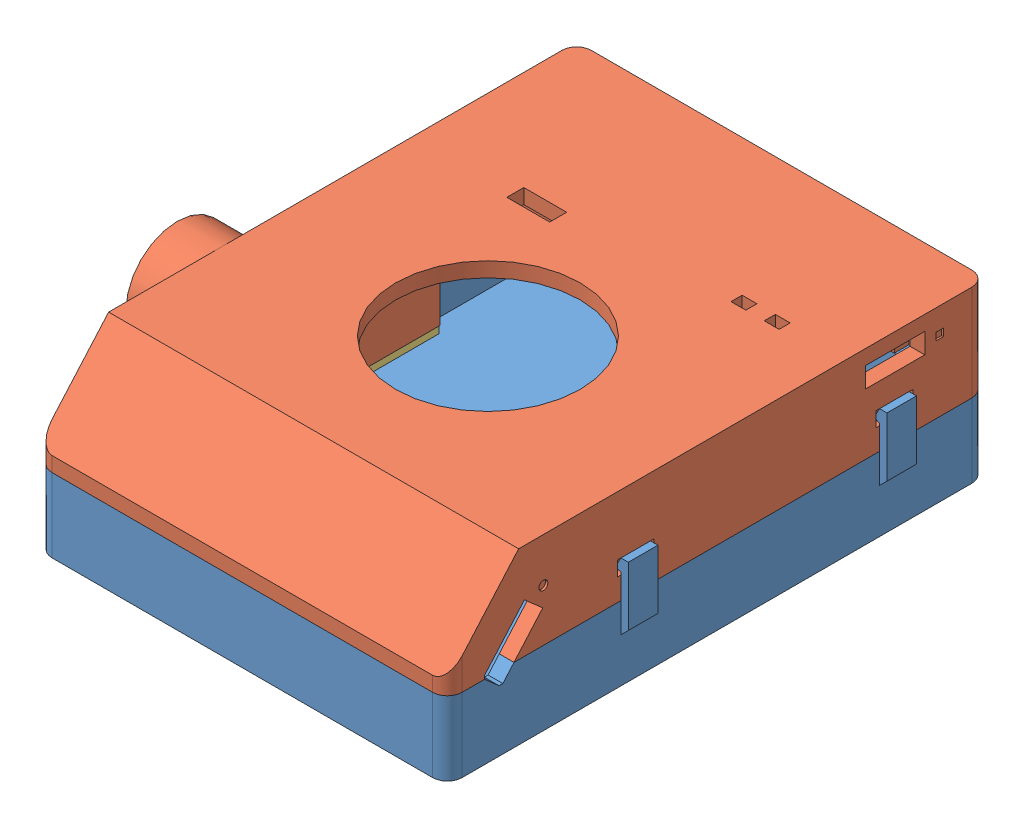
SolidWorks assembly Assem5, configuration Default. Lengths in mm.
Overall size (62.5 23 101.66).
4 component instances, 4 part files, 7 mates.
Components (placement in the parent):
- bottom shell 5-1: bottom shell 5 [Default] at (-8.039 40.5058 69.6202) size (57.5 15 73)
- top shell-1: top shell [Default] at (-8.039 63.5058 69.6202) x (1 0 0) z (0 0 -1) size (61.5 19 101.66)
- exit chamber cap 5-1: exit chamber cap 5 [Default] at (-23.889 50.5058 63.6202) x (0 0 -1) z (1 0 0) size (24.8 2.42 9.8)
- intake chamber cap 5-1: intake chamber cap 5 [Default] at (17.611 50.5058 62.6202) x (0 0 -1) z (1 0 0) size (25.8 2.42 9.8)
Mates (geometry in assembly coordinates):
- Coincident1: coincident anti-aligned: plane of bottom shell 5-1 through (-8.039 50.5058 69.6202) normal (0 1 0); plane of top shell-1 through (-8.039 50.5058 69.6202) normal (0 -1 0)
- Coincident2: coincident aligned: plane of bottom shell 5-1 through (-35.789 50.5058 106.1202) normal (0 0 1); plane of top shell-1 through (-35.789 50.5058 106.1202) normal (0 0 1)
- Coincident3: coincident aligned: plane of bottom shell 5-1 through (19.711 50.5058 106.1202) normal (1 0 0); plane of top shell-1 through (19.711 50.5058 33.1202) normal (1 0 0)
- Concentric1: concentric anti-aligned: cylinder of top shell-1 through (-29.539 54.7558 53.6955) axis (0 0 1) radius 3.25; cylinder of exit chamber cap 5-1 through (-29.539 54.7558 81.8702) axis (0 0 -1) radius 3.3
- Coincident4: coincident aligned: plane of top shell-1 through (-33.789 500063.5058 63.6202) normal (0 0 -1); plane of exit chamber cap 5-1 through (-23.889 51.5058 63.6202) normal (0 0 -1)
- Concentric2: concentric anti-aligned: cylinder of top shell-1 through (13.211 54.7558 53.4278) axis (0 0 1) radius 3.25; cylinder of intake chamber cap 5-1 through (13.211 54.7558 82.8702) axis (0 0 -1) radius 3.3
- Coincident5: coincident aligned: plane of top shell-1 through (7.711 40.394 62.6202) normal (0 0 -1); plane of intake chamber cap 5-1 through (17.611 51.5058 62.6202) normal (0 0 -1)
